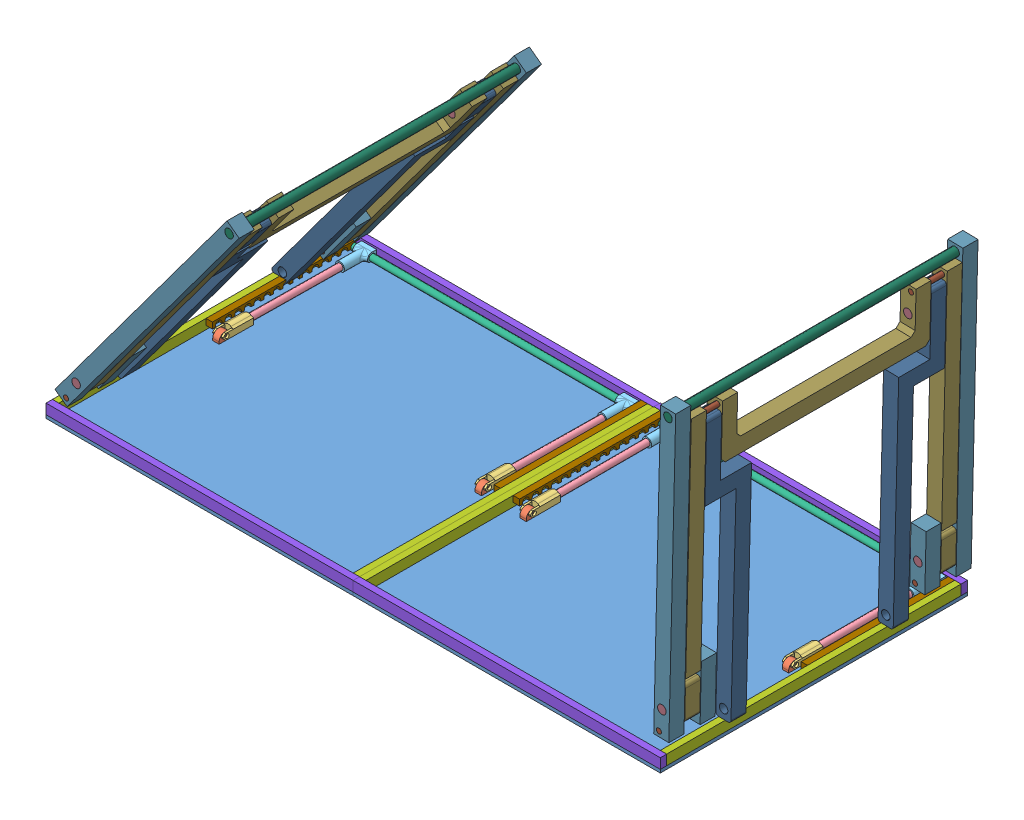
SolidWorks assembly PT-00-01 FULL ASSEMBLY, configuration Default. Lengths in mm.
Overall size (625.31 314.26 304.82).
62 component instances, 15 part files, 7 mates.
Components (placement in the parent):
- tabletop v2-1: tabletop v2 [Default] at (12.5523 197.1866 256.9696) size (304.8 13.23 304.82)
  - Tabletop-1: Tabletop [Default] at origin size (304.8 3.17 304.8)
  - Leg_AttatchV2-1: Leg_AttatchV2 [Default] at (-133.35 5.175 6) x (0 0 -1) z (1 0 0) size (12 8 6.35)
  - Leg_AttatchV2-2: Leg_AttatchV2 [Default] at (127 5.175 6) x (0 0 -1) z (1 0 0) size (12 8 6.35)
  - Leg_Adapter-1: Leg_Adapter [Default] at (-130.175 7.8466 -25.9979) x (1 0 0) z (0 0.012629 0.99992) size (10.35 10 30)
  - Leg_Adapter-2: Leg_Adapter [Default] at (130.175 7.8466 -25.9979) x (1 0 0) z (0 0.012629 0.99992) size (10.35 10 30)
  - Leg_v2-1: Leg_v2 [Default] at (130.175 6.4448 -136.9891) x (0.583854 -0.811794 0.010253) z (0 0.012629 0.99992) size (6.35 6.35 126)
  - Leg_v2-2: Leg_v2 [Default] at (-130.175 8.0361 -10.9991) x (-0.583854 -0.811794 0.010253) z (0 -0.012629 -0.99992) size (6.35 6.35 126)
  - Crossbar Adaptor-1: Crossbar Adaptor [Default] at (122.675 6.388 -141.4887) x (0 0.99992 -0.012629) z (1 0 0) size (9 29 15)
  - Crossbar Adaptor-2: Crossbar Adaptor [Default] at (-137.675 6.388 -141.4887) x (0 0.99992 -0.012629) z (1 0 0) size (9 29 15)
  - Crossbar_v2-1: Crossbar_v2 [Default] at (146.05 6.388 -141.4887) x (0 -0.987363 0.158473) z (-1 0 0) size (6.35 6.35 292.1)
  - Frame_Subassm-1: Frame_Subassm [Default] at (146.05 7.9165 -0.0083) x (0 0.001696 0.999999) z (1 0 0) size (304.8 10 304.8)
    - DepthFrame-1: DepthFrame [Default] at origin size (292.1 10 6.35)
    - WidthFrame-2: WidthFrame [Default] at (146.05 0 -146.05) x (0 0 1) z (0 1 0) size (304.8 6.35 10)
    - DepthFrame-2: DepthFrame [Default] at (0 0 -298.45) size (292.1 10 6.35)
    - WidthFrame-3: WidthFrame [Default] at (-146.05 0 -146.05) x (0 0 1) z (0 -1 0) size (304.8 6.35 10)
    - Slots-1: Slots [Default] at (-146.05 -5 -6.35) size (146.05 6 6.35)
    - Slots-2: Slots [Default] at (-146.05 -5 -292.1) size (146.05 6 6.35)
- second half tabletop v2-1: second half tabletop v2 [Default] at (317.3523 197.1866 256.9696) size (304.8 13.26 304.8)
  - Tabletop-1: Tabletop [Default] at origin size (304.8 3.17 304.8)
  - Leg_AttatchV2-1: Leg_AttatchV2 [Default] at (-133.35 5.175 6) x (0 0 -1) z (1 0 0) size (12 8 6.35)
  - Leg_AttatchV2-2: Leg_AttatchV2 [Default] at (127 5.175 6) x (0 0 -1) z (1 0 0) size (12 8 6.35)
  - Leg_Adapter-1: Leg_Adapter [Default] at (-130.175 8.1975 -26) x (1 0 0) z (0 -0.000865 1) size (10.35 10 30)
  - Leg_Adapter-2: Leg_Adapter [Default] at (130.175 8.1975 -26) x (1 0 0) z (0 -0.000865 1) size (10.35 10 30)
  - Leg_v2-1: Leg_v2 [Default] at (130.175 8.2935 -136.9999) x (0.583854 -0.811858 -0.000702) z (0 -0.000865 1) size (6.35 6.35 126)
  - Leg_v2-2: Leg_v2 [Default] at (-130.175 8.1845 -11) x (-0.583854 -0.811858 -0.000702) z (0 0.000865 -1) size (6.35 6.35 126)
  - Crossbar Adaptor-1: Crossbar Adaptor [Default] at (122.675 8.2974 -141.4999) x (0 1 0.000865) z (1 0 0) size (9 29 15)
  - Crossbar Adaptor-2: Crossbar Adaptor [Default] at (-137.675 8.2974 -141.4999) x (0 1 0.000865) z (1 0 0) size (9 29 15)
  - Crossbar_v2-1: Crossbar_v2 [Default] at (146.05 8.2974 -141.4999) x (0 -0.987363 0.158473) z (-1 0 0) size (6.35 6.35 292.1)
  - Frame_Subassm-1: Frame_Subassm [Default] at (146.05 8.2172 0.0014) x (0 -0.000277 1) z (1 0 0) size (304.8 10 304.8)
    - DepthFrame-1: DepthFrame [Default] at origin size (292.1 10 6.35)
    - WidthFrame-2: WidthFrame [Default] at (146.05 0 -146.05) x (0 0 1) z (0 1 0) size (304.8 6.35 10)
    - DepthFrame-2: DepthFrame [Default] at (0 0 -298.45) size (292.1 10 6.35)
    - WidthFrame-3: WidthFrame [Default] at (-146.05 0 -146.05) x (0 0 1) z (0 -1 0) size (304.8 6.35 10)
    - Slots-1: Slots [Default] at (-146.05 -5 -6.35) size (146.05 6 6.35)
    - Slots-2: Slots [Default] at (-146.05 -5 -292.1) size (146.05 6 6.35)
- PT-00-02 LEG SUB ASSEMBLY-1: PT-00-02 LEG SUB ASSEMBLY [Default] at (-317.5847 219.776 184.236) x (0 0.001696 0.999999) z (0.594645 0.803987 -0.001364) size (745.84 15.35 599.69)
  - PT-01-03 BASE LEG-1: PT-01-03 BASE LEG [Default] at (-15.2997 145.7238 377.8144) size (238 15 280)
  - PT-02-02 5mm DOWEL-1: PT-02-02 5mm DOWEL [Default] at (-15.7997 150.7238 381.8144) x (0 0 1) z (-1 0 0) size (5 5 46)
  - PT-02-02 5mm DOWEL-2: PT-02-02 5mm DOWEL [Default] at (207.2003 150.7238 381.8144) x (0 0 1) z (-1 0 0) size (5 5 46)
  - PT-01-02 MIDDLE LEG-1: PT-01-02 MIDDLE LEG [Default] at (-61.7997 160.7238 121.8144) x (1 0 0) z (0 0 -1) size (269 15 265)
  - PT-02-01 8.5mm DOWEL-1: PT-02-01 8.5mm DOWEL [Default] at (-15.7997 153.2238 361.8144) x (0 0 1) z (-1 0 0) size (8.5 8.5 46)
  - PT-02-01 8.5mm DOWEL-2: PT-02-01 8.5mm DOWEL [Default] at (161.2003 153.2238 361.8144) x (0 -0.001444 -0.999999) z (1 0 0) size (8.5 8.5 46)
  - PT-02-02 5mm DOWEL-3: PT-02-02 5mm DOWEL [Default] at (-31.2997 155.699 117.8113) x (0 0.000012 1) z (-1 0 0) size (5 5 46)
  - PT-02-02 5mm DOWEL-4: PT-02-02 5mm DOWEL [Default] at (176.7003 155.699 117.8113) x (0 0 -1) z (1 0 0) size (5 5 46)
  - PT-02-01 8.5mm DOWEL-3: PT-02-01 8.5mm DOWEL [Default] at (-31.2997 153.2238 137.8144) x (0 0 1) z (-1 0 0) size (8.5 8.5 46)
  - PT-02-01 8.5mm DOWEL-4: PT-02-01 8.5mm DOWEL [Default] at (222.7003 153.2238 137.8144) x (0 0 1) z (-1 0 0) size (8.5 8.5 46)
  - PT-01-01 LARGEST LEG-1: PT-01-01 LARGEST LEG [Default] at (-77.2997 146.0469 398.8235) x (1 0 0) z (0 0.001238 0.999999) size (300 15 286)
  - PT-02-01 8.5mm DOWEL LONG-1: PT-02-01 8.5mm DOWEL LONG [Default] at (222.7003 153.5385 392.0642) x (0 0.990229 0.139451) z (-1 0 0) size (8.5 8.5 300)
- PT-00-02 LEG SUB ASSEMBLY-2: PT-00-02 LEG SUB ASSEMBLY [Default] at (618.6059 108.6177 329.6445) x (0 0.000277 -1) z (0.025251 0.999681 0.000277) size (745.84 15.35 599.69)
  - PT-01-03 BASE LEG-1: PT-01-03 BASE LEG [Default] at (-15.2997 145.7238 377.8144) size (238 15 280)
  - PT-02-02 5mm DOWEL-1: PT-02-02 5mm DOWEL [Default] at (-15.7997 150.7238 381.8144) x (0 0 1) z (-1 0 0) size (5 5 46)
  - PT-02-02 5mm DOWEL-2: PT-02-02 5mm DOWEL [Default] at (207.2003 150.7238 381.8144) x (0 0 1) z (-1 0 0) size (5 5 46)
  - PT-01-02 MIDDLE LEG-1: PT-01-02 MIDDLE LEG [Default] at (-61.7997 160.7238 121.8144) x (1 0 0) z (0 0 -1) size (269 15 265)
  - PT-02-01 8.5mm DOWEL-1: PT-02-01 8.5mm DOWEL [Default] at (-15.7997 153.2238 361.8144) x (0 0 1) z (-1 0 0) size (8.5 8.5 46)
  - PT-02-01 8.5mm DOWEL-2: PT-02-01 8.5mm DOWEL [Default] at (161.2003 153.2238 361.8144) x (0 -0.001444 -0.999999) z (1 0 0) size (8.5 8.5 46)
  - PT-02-02 5mm DOWEL-3: PT-02-02 5mm DOWEL [Default] at (-31.2997 155.699 117.8113) x (0 0.000012 1) z (-1 0 0) size (5 5 46)
  - PT-02-02 5mm DOWEL-4: PT-02-02 5mm DOWEL [Default] at (176.7003 155.699 117.8113) x (0 0 -1) z (1 0 0) size (5 5 46)
  - PT-02-01 8.5mm DOWEL-3: PT-02-01 8.5mm DOWEL [Default] at (-31.2997 153.2238 137.8144) x (0 0 1) z (-1 0 0) size (8.5 8.5 46)
  - PT-02-01 8.5mm DOWEL-4: PT-02-01 8.5mm DOWEL [Default] at (222.7003 153.2238 137.8144) x (0 0 1) z (-1 0 0) size (8.5 8.5 46)
  - PT-01-01 LARGEST LEG-1: PT-01-01 LARGEST LEG [Default] at (-77.2997 146.0469 398.8235) x (1 0 0) z (0 0.001238 0.999999) size (300 15 286)
  - PT-02-01 8.5mm DOWEL LONG-1: PT-02-01 8.5mm DOWEL LONG [Default] at (222.7003 153.5385 392.0642) x (0 0.990229 0.139451) z (-1 0 0) size (8.5 8.5 300)
Mates (geometry in assembly coordinates):
- Coincident3: coincident anti-aligned: line of tabletop v2-1/Tabletop-1 through (164.9523 197.1866 409.3696) axis (0 0 -1); line of second half tabletop v2-1/Tabletop-1 through (164.9523 197.1866 104.5696) axis (0 0 1)
- Coincident4: coincident aligned: plane of tabletop v2-1/Tabletop-1 through (164.9523 200.3616 409.3696) normal (0 0 1); plane of second half tabletop v2-1/Tabletop-1 through (469.7523 200.3616 409.3696) normal (0 0 1)
- Coincident5: coincident anti-aligned: line of tabletop v2-1/Frame_Subassm-1/DepthFrame-2 through (-139.8477 209.8554 110.9031) axis (0 0.001696 0.999999); line of PT-00-02 LEG SUB ASSEMBLY-1/PT-01-03 BASE LEG-1 through (-139.8477 209.9793 183.953) axis (0 -0.001696 -0.999999)
- Width1: width anti-aligned: plane of tabletop v2-1/Frame_Subassm-1/WidthFrame-3 through (12.5523 204.8446 104.5616) normal (0 -0.001696 -0.999999); plane of tabletop v2-1/Frame_Subassm-1/WidthFrame-2 through (12.5523 205.3616 409.3611) normal (0 0.001696 0.999999); plane of PT-00-02 LEG SUB ASSEMBLY-1/PT-01-01 LARGEST LEG-1 through (49.0425 445.0221 406.5546) normal (0 0.001696 0.999999); plane of PT-00-02 LEG SUB ASSEMBLY-1/PT-01-01 LARGEST LEG-1 through (49.0425 444.5133 106.5551) normal (0 -0.001696 -0.999999)
- Width2: width anti-aligned: plane of second half tabletop v2-1/Frame_Subassm-1/WidthFrame-3 through (317.3523 205.446 104.571) normal (0 0.000277 -1); plane of second half tabletop v2-1/Frame_Subassm-1/WidthFrame-2 through (317.3523 205.3616 409.371) normal (0 -0.000277 1); plane of PT-00-02 LEG SUB ASSEMBLY-2/PT-01-01 LARGEST LEG-1 through (467.6807 511.3407 407.0558) normal (0 -0.000277 1); plane of PT-00-02 LEG SUB ASSEMBLY-2/PT-01-01 LARGEST LEG-1 through (467.6807 511.4238 107.0558) normal (0 0.000277 -1)
- Coincident9: coincident anti-aligned: line of second half tabletop v2-1/Frame_Subassm-1/DepthFrame-1 through (463.4023 210.4443 110.9224) axis (0 -0.000277 1); line of PT-00-02 LEG SUB ASSEMBLY-2/PT-01-03 BASE LEG-1 through (463.4023 210.3794 344.9724) axis (0 0.000277 -1)
- Parallel1: parallel anti-aligned: plane of second half tabletop v2-1/Tabletop-1 through (317.3523 197.1866 256.9696) normal (0 -1 0)
